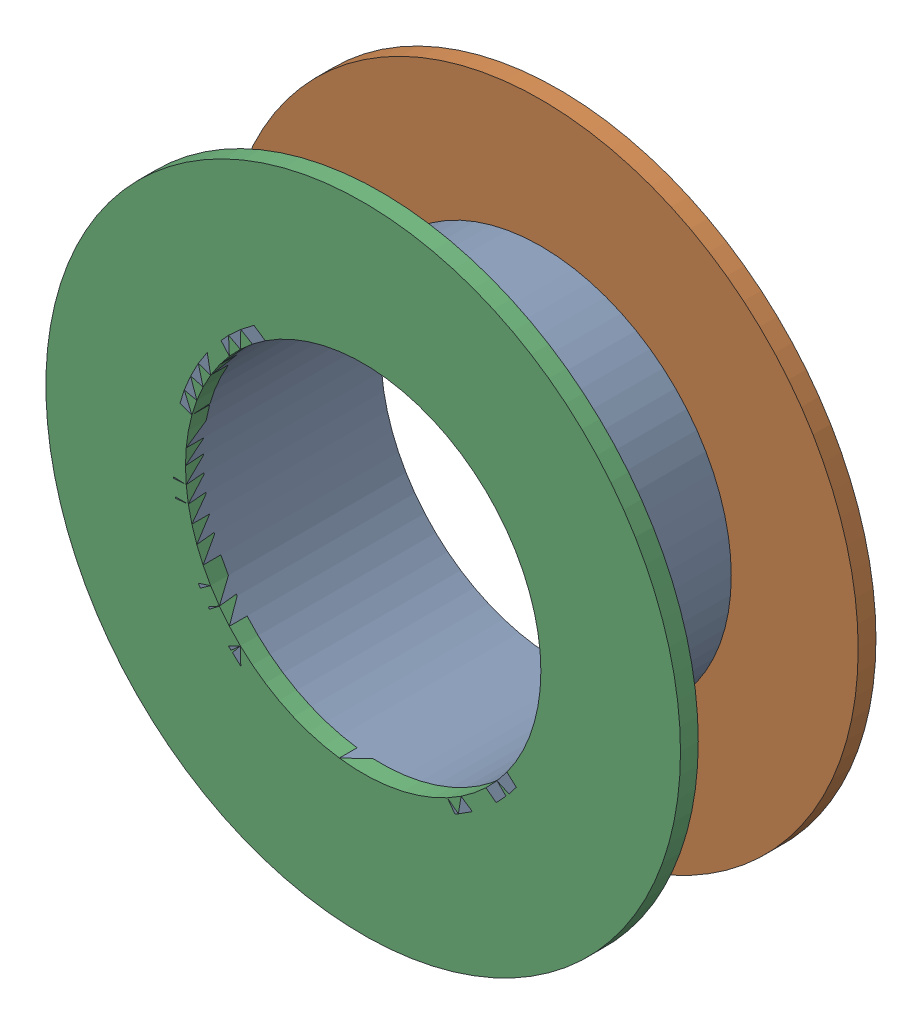
SolidWorks assembly Via (16.7mm,22.5mm) from Top Layer to Bottom Layer, configuration Predeterminado. Lengths in mm.
Overall size (1.27 1.27 0.39).
6 component instances, 2 part files, 0 mates.
Components (placement in the parent):
- Via Hole-1: Via Hole [Predeterminado] at (16.7 22.5 -0.4013) size (0.76 0.76 0.39)
  - Via Hole-Part-1-1: Via Hole-Part-1 [Predeterminado] at origin size (0.76 0.76 0.39)
- Via Top Layer-1: Via Top Layer [Predeterminado] at (16.7 22.5 -0.4013) size (1.27 1.27 0.04)
  - Via Top Layer-Part-1-1: Via Top Layer-Part-1 [Predeterminado] at origin size (1.27 1.27 0.04)
- Via Top Layer-2: Via Top Layer [Predeterminado] at (16.7 22.5 -0.0457) size (1.27 1.27 0.04)
  - Via Top Layer-Part-1-1: Via Top Layer-Part-1 [Predeterminado] at origin size (1.27 1.27 0.04)
